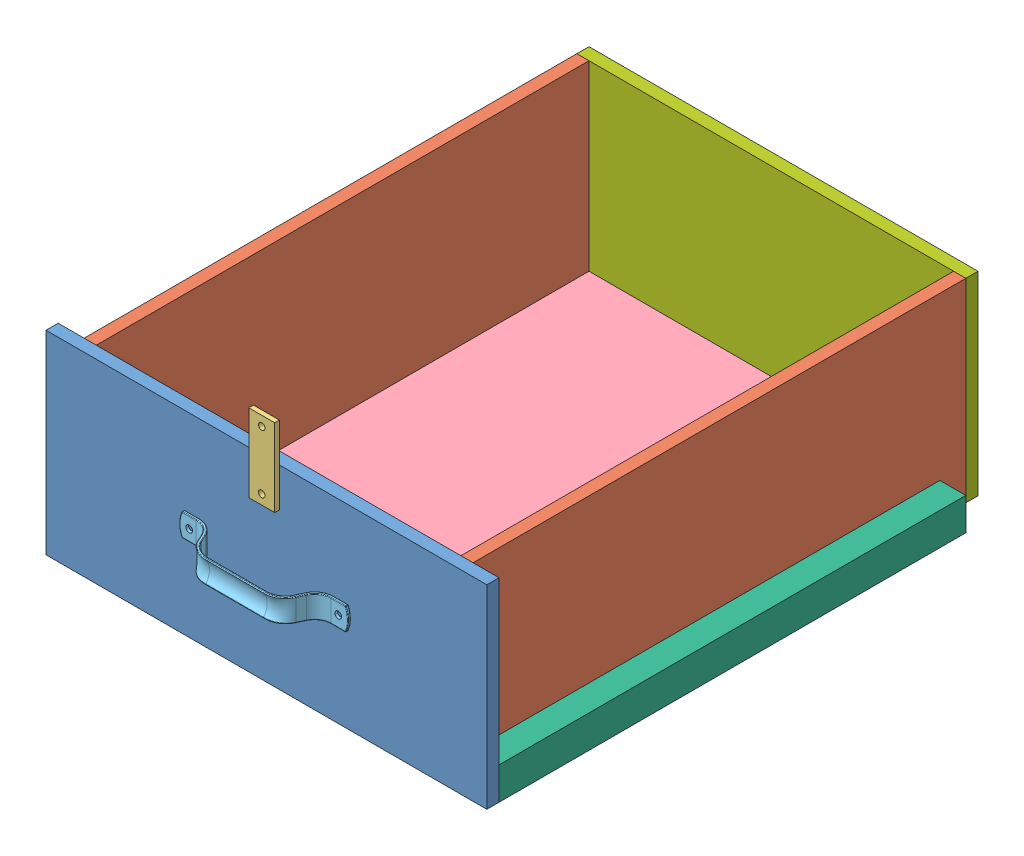
SolidWorks assembly Drawer Assembly, configuration Default. Lengths in mm.
Overall size (431.8 228.6 538.86).
9 component instances, 7 part files, 25 mates.
Components (placement in the parent):
- Drawer Front and back-1: Drawer Front and back [Default] at (89.7609 213.6851 304.0669) size (431.8 190.5 11.94)
- Drawer Side-1: Drawer Side [Default] at (-100.7391 213.6851 62.7669) size (11.94 190.5 482.6)
- Drawer Side-2: Drawer Side [Default] at (268.3229 213.6851 62.7669) size (11.94 190.5 482.6)
- 1030A4_Flat-Surface Bracket-1: 1030A4_Flat-Surface Bracket [1030A4] at (89.7609 308.9351 318.2909) x (0 1 0) z (0 0 1) size (76.2 25.4 4.57)
- Drawer bottom-2: Drawer bottom [Default] at (89.7609 118.4351 62.7669) size (357.12 11.94 482.6)
- 5185A1_Unthreaded-Hole Rectangular Pull Handle-1: 5185A1_Unthreaded-Hole Rectangular Pull Handle [5185A1] at (89.7609 213.2089 316.0049) size (165.1 24.16 32.38)
- Drawer Rail-3: Drawer Rail [Default] at (-113.4391 134.3101 -153.1331) size (25.4 31.75 457.2)
- Drawer Rail-4: Drawer Rail [Default] at (292.9609 134.3101 -153.1331) size (25.4 31.75 457.2)
- Drawer back panel-1: Drawer back panel [Default] at (89.7609 213.6851 -190.4711) size (381 190.5 11.94)
Mates (geometry in assembly coordinates):
- Coincident1: coincident anti-aligned: plane of Drawer Front and back-1 through (89.7609 213.6851 304.0669) normal (0 0 -1); plane of Drawer Side-2 through (280.2609 118.4351 304.0669) normal (0 0 1)
- Distance8: distance = 25.4 mm aligned: plane of Drawer Front and back-1 through (305.6609 118.4351 316.0049) normal (1 0 0); plane of Drawer Side-2 through (280.2609 213.6851 62.7669) normal (1 0 0)
- Coincident3: coincident aligned: plane of Drawer Front and back-1 through (-126.1391 308.9351 316.0049) normal (0 1 0); plane of Drawer Side-2 through (280.2609 308.9351 304.0669) normal (0 1 0)
- Coincident4: coincident anti-aligned: plane of Drawer Front and back-1 through (89.7609 213.6851 304.0669) normal (0 0 -1); plane of Drawer Side-1 through (-88.8011 118.4351 304.0669) normal (0 0 1)
- Distance9: distance = 25.4 mm aligned: plane of Drawer Front and back-1 through (-126.1391 118.4351 316.0049) normal (-1 0 0); plane of Drawer Side-1 through (-100.7391 213.6851 62.7669) normal (-1 0 0)
- Coincident6: coincident aligned: plane of Drawer Front and back-1 through (-126.1391 308.9351 316.0049) normal (0 1 0); plane of Drawer Side-1 through (-88.8011 308.9351 304.0669) normal (0 1 0)
- Parallel2: parallel anti-aligned: plane of Drawer Front and back-1 through (-126.1391 308.9351 316.0049) normal (0 1 0); plane of 1030A4_Flat-Surface Bracket-1 through (77.0609 270.8351 320.5769) normal (0 -1 0)
- Distance4: distance = 38.1 mm anti-aligned: plane of 1030A4_Flat-Surface Bracket-1 through (77.0609 270.8351 320.5769) normal (0 -1 0); plane of Drawer Front and back-1 through (-126.1391 308.9351 316.0049) normal (0 1 0)
- Coincident28: coincident anti-aligned: plane of Drawer Front and back-1 through (89.7609 213.6851 316.0049) normal (0 0 1); plane of 1030A4_Flat-Surface Bracket-1 through (89.7609 308.9351 316.0049) normal (0 0 -1)
- Distance5: distance = 203.2 mm aligned: plane of 1030A4_Flat-Surface Bracket-1 through (77.0609 270.8351 320.5769) normal (-1 0 0); plane of Drawer Front and back-1 through (-126.1391 118.4351 316.0049) normal (-1 0 0)
- Coincident36: coincident anti-aligned: plane of Drawer Side-2 through (268.3229 213.6851 62.7669) normal (-1 0 0); plane of Drawer bottom-2 through (268.3229 130.3731 304.0669) normal (1 0 0)
- Coincident39: coincident anti-aligned: plane of Drawer Front and back-1 through (89.7609 213.6851 316.0049) normal (0 0 1); plane of 5185A1_Unthreaded-Hole Rectangular Pull Handle-1 through (155.8721 256.5476 316.0049) normal (0 0 -1)
- Distance6: distance = 60.325 mm: cylinder of 5185A1_Unthreaded-Hole Rectangular Pull Handle-1 through (162.7859 213.2089 316.0049) axis (0 0 1) radius 3.302; plane of 1030A4_Flat-Surface Bracket-1 through (102.4609 270.8351 320.5769) normal (1 0 0)
- Distance7: distance = 84.6137 mm aligned: plane of 5185A1_Unthreaded-Hole Rectangular Pull Handle-1 through (61.4837 224.3214 347.7549) normal (0 1 0); plane of Drawer Front and back-1 through (-126.1391 308.9351 316.0049) normal (0 1 0)
- Coincident47: coincident aligned: plane of Drawer bottom-2 through (89.7609 118.4351 62.7669) normal (0 -1 0); plane of Drawer Rail-3 through (-126.1391 118.4351 304.0669) normal (0 -1 0)
- Coincident48: coincident anti-aligned: plane of Drawer Side-1 through (-100.7391 213.6851 62.7669) normal (-1 0 0); plane of Drawer Rail-3 through (-100.7391 118.4351 304.0669) normal (1 0 0)
- Coincident49: coincident anti-aligned: plane of Drawer Front and back-1 through (89.7609 213.6851 304.0669) normal (0 0 -1); plane of Drawer Rail-3 through (-113.4391 134.3101 304.0669) normal (0 0 1)
- Coincident50: coincident anti-aligned: plane of Drawer Side-2 through (280.2609 213.6851 62.7669) normal (1 0 0); plane of Drawer Rail-4 through (280.2609 118.4351 304.0669) normal (-1 0 0)
- Coincident51: coincident aligned: plane of Drawer Side-2 through (280.2609 118.4351 304.0669) normal (0 -1 0); plane of Drawer Rail-4 through (280.2609 118.4351 304.0669) normal (0 -1 0)
- Coincident52: coincident: line of Drawer Front and back-1 through (305.6609 118.4351 304.0669) axis (0 1 0); plane of Drawer Rail-4 through (292.9609 134.3101 304.0669) normal (0 0 1)
- Coincident53: coincident anti-aligned: plane of Drawer Side-1 through (-88.8011 118.4351 -178.5331) normal (0 0 -1); plane of Drawer back panel-1 through (89.7609 213.6851 -178.5331) normal (0 0 1)
- Coincident54: coincident aligned: plane of Drawer Side-2 through (280.2609 213.6851 62.7669) normal (1 0 0); plane of Drawer back panel-1 through (280.2609 118.4351 -178.5331) normal (1 0 0)
- Coincident55: coincident aligned: plane of Drawer bottom-2 through (89.7609 118.4351 62.7669) normal (0 -1 0); plane of Drawer back panel-1 through (-100.7391 118.4351 -178.5331) normal (0 -1 0)
- Coincident56: coincident aligned: plane of Drawer Side-2 through (280.2609 118.4351 304.0669) normal (0 -1 0); plane of Drawer bottom-2 through (89.7609 118.4351 62.7669) normal (0 -1 0)
- Coincident57: coincident anti-aligned: plane of Drawer Front and back-1 through (89.7609 213.6851 304.0669) normal (0 0 -1); plane of Drawer bottom-2 through (-88.8011 130.3731 304.0669) normal (0 0 1)
